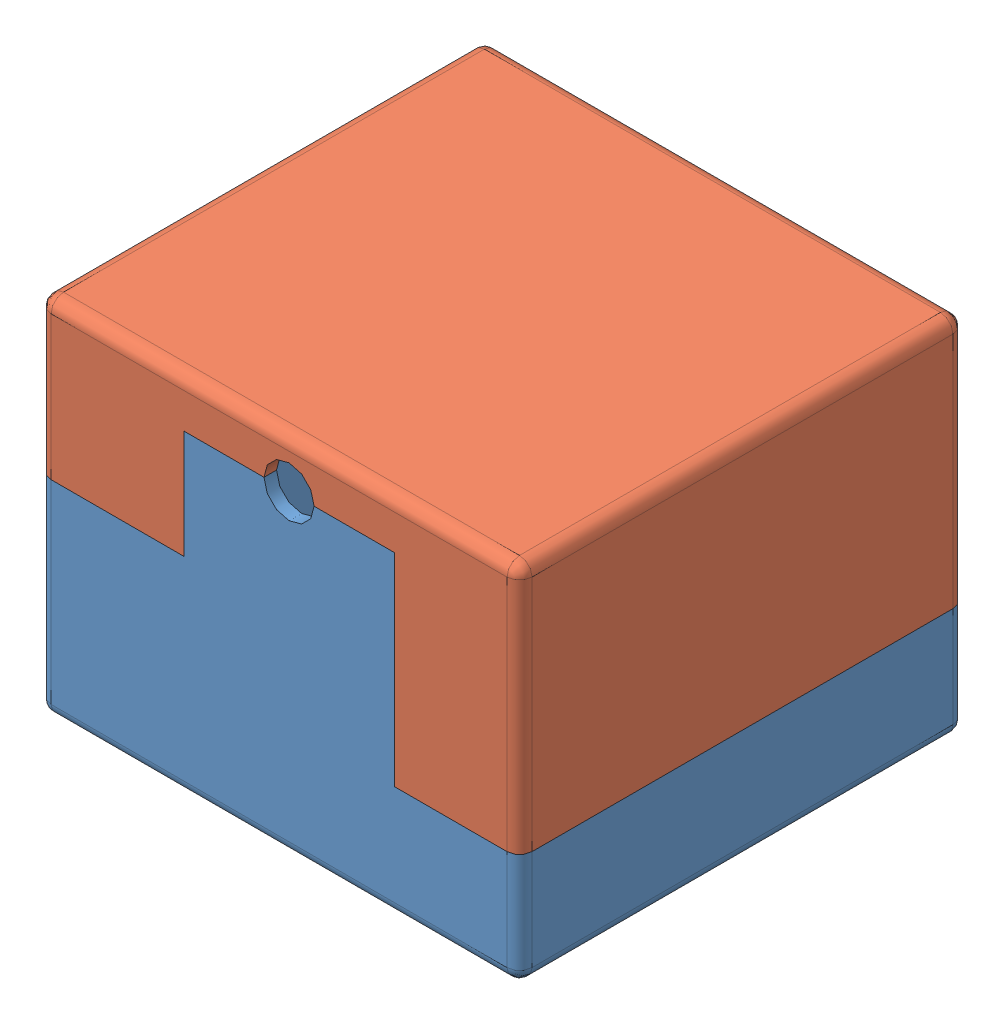
SolidWorks assembly assbyDriverCase, configuration Default. Lengths in mm.
Overall size (96 72.5 89).
2 component instances, 2 part files, 8 mates.
Components (placement in the parent):
- motorqiegedibu-1: motorqiegedibu [Default] at (-49.4261 16.2679 50.4331) size (96 63 89)
- motorqiegedibu1-1: motorqiegedibu1 [Default] at (-49.4261 88.7679 139.4331) x (1 0 0) z (0 0 -1) size (96 49.95 89)
Mates (geometry in assembly coordinates):
- Coincident3: coincident anti-aligned: plane of motorqiegedibu-1 through (21.5739 57.6079 139.4331) normal (0 1 0); plane of motorqiegedibu1-1 through (21.5739 57.6079 139.4331) normal (0 -1 0)
- Coincident5: coincident anti-aligned: plane of motorqiegedibu-1 through (21.5739 38.8179 139.4331) normal (1 0 0); plane of motorqiegedibu1-1 through (21.5739 38.8179 139.4331) normal (-1 0 0)
- Coincident7: coincident anti-aligned: plane of motorqiegedibu-1 through (-20.4261 79.2679 136.9331) normal (0 1 0); plane of motorqiegedibu1-1 through (21.5739 79.2679 136.9331) normal (0 -1 0)
- Parallel4: parallel aligned: plane of motorqiegedibu-1 through (-49.4261 88.7679 139.4331) normal (0 0 1); plane of motorqiegedibu1-1 through (-49.4261 16.2679 139.4331) normal (0 0 1)
- Parallel5: parallel aligned: plane of motorqiegedibu-1 through (46.5739 88.7679 50.4331) normal (1 0 0); plane of motorqiegedibu1-1 through (46.5739 16.2679 139.4331) normal (1 0 0)
- Parallel6: parallel aligned: plane of motorqiegedibu-1 through (-49.4261 88.7679 50.4331) normal (0 0 -1); plane of motorqiegedibu1-1 through (-49.4261 16.2679 50.4331) normal (0 0 -1)
- Parallel8: parallel aligned: plane of motorqiegedibu-1 through (-49.4261 88.7679 50.4331) normal (-1 0 0); plane of motorqiegedibu1-1 through (-49.4261 16.2679 139.4331) normal (-1 0 0)
- Distance1: distance = 0 mm aligned: plane of motorqiegedibu-1 through (-49.4261 88.7679 50.4331) normal (0 0 -1); plane of motorqiegedibu1-1 through (-49.4261 16.2679 50.4331) normal (0 0 -1)
